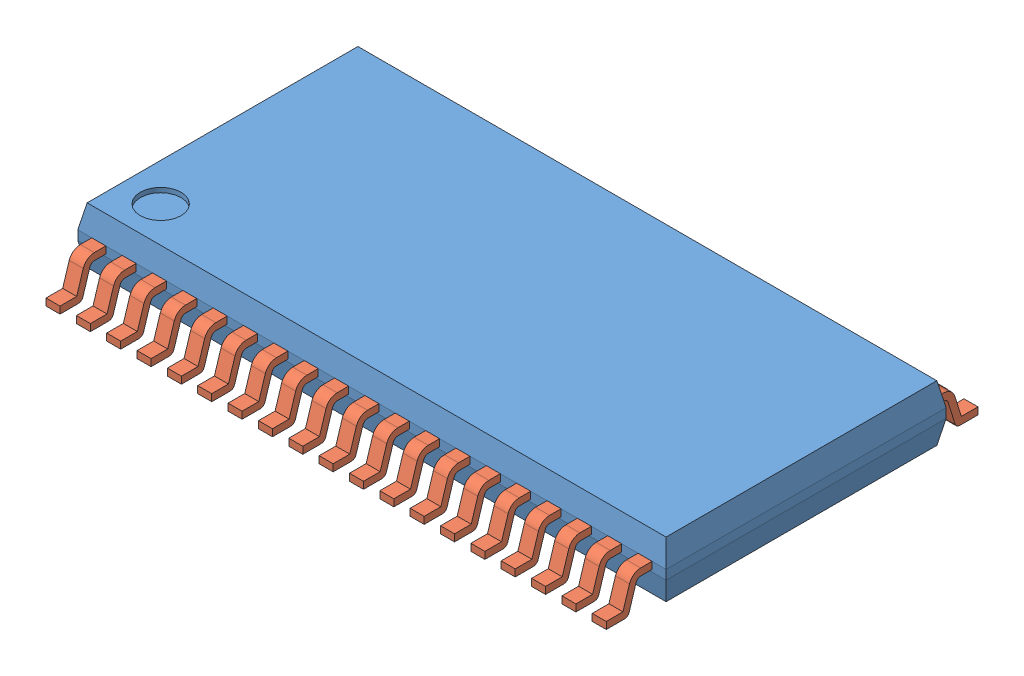
SolidWorks assembly U2, configuration Défaut. Lengths in mm.
Overall size (12.6 1.27 7.96).
39 component instances, 2 part files, 114 mates.
Components (placement in the parent):
- U2_Boitier-1: U2_Boitier [Défaut] at (4.9869 3.6612 3) size (12.6 1.2 6)
- U2_Pin-1: U2_Pin [Défaut] at (11.1369 3.5862 3.9812) x (0 0 -1) z (1 0 0) size (0.98 0.78 0.3)
- U2_Pin-2: U2_Pin [Défaut] at (10.4869 3.5862 3.9812) x (0 0 -1) z (1 0 0) size (0.98 0.78 0.3)
- U2_Pin-3: U2_Pin [Défaut] at (9.8369 3.5862 3.9812) x (0 0 -1) z (1 0 0) size (0.98 0.78 0.3)
- U2_Pin-4: U2_Pin [Défaut] at (9.1869 3.5862 3.9812) x (0 0 -1) z (1 0 0) size (0.98 0.78 0.3)
- U2_Pin-5: U2_Pin [Défaut] at (8.5369 3.5862 3.9812) x (0 0 -1) z (1 0 0) size (0.98 0.78 0.3)
- U2_Pin-6: U2_Pin [Défaut] at (7.8869 3.5862 3.9812) x (0 0 -1) z (1 0 0) size (0.98 0.78 0.3)
- U2_Pin-7: U2_Pin [Défaut] at (7.2369 3.5862 3.9812) x (0 0 -1) z (1 0 0) size (0.98 0.78 0.3)
- U2_Pin-8: U2_Pin [Défaut] at (6.5869 3.5862 3.9812) x (0 0 -1) z (1 0 0) size (0.98 0.78 0.3)
- U2_Pin-9: U2_Pin [Défaut] at (5.9369 3.5862 3.9812) x (0 0 -1) z (1 0 0) size (0.98 0.78 0.3)
- U2_Pin-12: U2_Pin [Défaut] at (11.7869 3.5862 3.9812) x (0 0 -1) z (1 0 0) size (0.98 0.78 0.3)
- U2_Pin-13: U2_Pin [Défaut] at (12.4369 3.5862 3.9812) x (0 0 -1) z (1 0 0) size (0.98 0.78 0.3)
- U2_Pin-14: U2_Pin [Défaut] at (13.0869 3.5862 3.9812) x (0 0 -1) z (1 0 0) size (0.98 0.78 0.3)
- U2_Pin-15: U2_Pin [Défaut] at (13.7369 3.5862 3.9812) x (0 0 -1) z (1 0 0) size (0.98 0.78 0.3)
- U2_Pin-16: U2_Pin [Défaut] at (14.3869 3.5862 3.9812) x (0 0 -1) z (1 0 0) size (0.98 0.78 0.3)
- U2_Pin-17: U2_Pin [Défaut] at (15.0369 3.5862 3.9812) x (0 0 -1) z (1 0 0) size (0.98 0.78 0.3)
- U2_Pin-18: U2_Pin [Défaut] at (15.6869 3.5862 3.9812) x (0 0 -1) z (1 0 0) size (0.98 0.78 0.3)
- U2_Pin-19: U2_Pin [Défaut] at (16.3369 3.5862 3.9812) x (0 0 -1) z (1 0 0) size (0.98 0.78 0.3)
- U2_Pin-21: U2_Pin [Défaut] at (5.2869 3.5862 3.9812) x (0 0 -1) z (1 0 0) size (0.98 0.78 0.3)
- U2_Pin-22: U2_Pin [Défaut] at (16.9869 3.5862 3.9812) x (0 0 -1) z (1 0 0) size (0.98 0.78 0.3)
- U2_Pin-23: U2_Pin [Défaut] at (11.4369 3.5862 -3.9812) x (0 0 1) z (-1 0 0) size (0.98 0.78 0.3)
- U2_Pin-24: U2_Pin [Défaut] at (12.0869 3.5862 -3.9812) x (0 0 1) z (-1 0 0) size (0.98 0.78 0.3)
- U2_Pin-26: U2_Pin [Défaut] at (12.7369 3.5862 -3.9812) x (0 0 1) z (-1 0 0) size (0.98 0.78 0.3)
- U2_Pin-27: U2_Pin [Défaut] at (13.3869 3.5862 -3.9812) x (0 0 1) z (-1 0 0) size (0.98 0.78 0.3)
- U2_Pin-28: U2_Pin [Défaut] at (14.0369 3.5862 -3.9812) x (0 0 1) z (-1 0 0) size (0.98 0.78 0.3)
- U2_Pin-29: U2_Pin [Défaut] at (14.6869 3.5862 -3.9812) x (0 0 1) z (-1 0 0) size (0.98 0.78 0.3)
- U2_Pin-30: U2_Pin [Défaut] at (15.3369 3.5862 -3.9812) x (0 0 1) z (-1 0 0) size (0.98 0.78 0.3)
- U2_Pin-31: U2_Pin [Défaut] at (15.9869 3.5862 -3.9812) x (0 0 1) z (-1 0 0) size (0.98 0.78 0.3)
- U2_Pin-32: U2_Pin [Défaut] at (16.6369 3.5862 -3.9812) x (0 0 1) z (-1 0 0) size (0.98 0.78 0.3)
- U2_Pin-33: U2_Pin [Défaut] at (17.2869 3.5862 -3.9812) x (0 0 1) z (-1 0 0) size (0.98 0.78 0.3)
- U2_Pin-34: U2_Pin [Défaut] at (10.7869 3.5862 -3.9812) x (0 0 1) z (-1 0 0) size (0.98 0.78 0.3)
- U2_Pin-35: U2_Pin [Défaut] at (10.1369 3.5862 -3.9812) x (0 0 1) z (-1 0 0) size (0.98 0.78 0.3)
- U2_Pin-36: U2_Pin [Défaut] at (9.4869 3.5862 -3.9812) x (0 0 1) z (-1 0 0) size (0.98 0.78 0.3)
- U2_Pin-37: U2_Pin [Défaut] at (8.8369 3.5862 -3.9812) x (0 0 1) z (-1 0 0) size (0.98 0.78 0.3)
- U2_Pin-38: U2_Pin [Défaut] at (8.1869 3.5862 -3.9812) x (0 0 1) z (-1 0 0) size (0.98 0.78 0.3)
- U2_Pin-39: U2_Pin [Défaut] at (7.5369 3.5862 -3.9812) x (0 0 1) z (-1 0 0) size (0.98 0.78 0.3)
- U2_Pin-40: U2_Pin [Défaut] at (6.8869 3.5862 -3.9812) x (0 0 1) z (-1 0 0) size (0.98 0.78 0.3)
- U2_Pin-41: U2_Pin [Défaut] at (6.2369 3.5862 -3.9812) x (0 0 1) z (-1 0 0) size (0.98 0.78 0.3)
- U2_Pin-42: U2_Pin [Défaut] at (5.5869 3.5862 -3.9812) x (0 0 1) z (-1 0 0) size (0.98 0.78 0.3)
Mates (geometry in assembly coordinates):
- Coïncidente1: coincident anti-aligned: plane of U2_Boitier-1 through (4.9869 4.8612 3) normal (0 0 1); plane of U2_Pin-1 through (11.4369 4.3612 3) normal (0 0 -1)
- Coïncidente2: coincident aligned: line of U2_Boitier-1 through (17.5869 4.3612 3) axis (-1 0 0); line of U2_Pin-1 through (11.4369 4.3612 3) axis (-1 0 0)
- Distance1: distance = 6.15 mm aligned: plane of U2_Pin-1 through (11.1369 3.6862 3.5874) normal (-1 0 0); plane of U2_Boitier-1 through (4.9869 4.8612 3) normal (-1 0 0)
- Coïncidente4: coincident anti-aligned: plane of U2_Boitier-1 through (4.9869 4.8612 3) normal (0 0 1); plane of U2_Pin-2 through (10.7869 4.3612 3) normal (0 0 -1)
- Coïncidente5: coincident aligned: line of U2_Boitier-1 through (17.5869 4.3612 3) axis (-1 0 0); line of U2_Pin-2 through (10.7869 4.3612 3) axis (-1 0 0)
- Distance2: distance = 0.35 mm anti-aligned: plane of U2_Pin-2 through (10.7869 3.6862 3.5874) normal (1 0 0); plane of U2_Pin-1 through (11.1369 3.6862 3.5874) normal (-1 0 0)
- Coïncidente7: coincident anti-aligned: plane of U2_Boitier-1 through (4.9869 4.8612 3) normal (0 0 1); plane of U2_Pin-3 through (10.1369 4.3612 3) normal (0 0 -1)
- Coïncidente8: coincident aligned: line of U2_Boitier-1 through (17.5869 4.3612 3) axis (-1 0 0); line of U2_Pin-3 through (10.1369 4.3612 3) axis (-1 0 0)
- Distance3: distance = 0.35 mm anti-aligned: plane of U2_Pin-3 through (10.1369 3.6862 3.5874) normal (1 0 0); plane of U2_Pin-2 through (10.4869 3.6862 3.5874) normal (-1 0 0)
- Coïncidente9: coincident anti-aligned: plane of U2_Boitier-1 through (4.9869 4.8612 3) normal (0 0 1); plane of U2_Pin-4 through (9.4869 4.3612 3) normal (0 0 -1)
- Coïncidente10: coincident aligned: line of U2_Boitier-1 through (17.5869 4.3612 3) axis (-1 0 0); line of U2_Pin-4 through (9.4869 4.3612 3) axis (-1 0 0)
- Distance4: distance = 0.35 mm anti-aligned: plane of U2_Pin-4 through (9.4869 3.6862 3.5874) normal (1 0 0); plane of U2_Pin-3 through (9.8369 3.6862 3.5874) normal (-1 0 0)
- Coïncidente11: coincident anti-aligned: plane of U2_Boitier-1 through (4.9869 4.8612 3) normal (0 0 1); plane of U2_Pin-5 through (8.8369 4.3612 3) normal (0 0 -1)
- Coïncidente12: coincident aligned: line of U2_Boitier-1 through (17.5869 4.3612 3) axis (-1 0 0); line of U2_Pin-5 through (8.8369 4.3612 3) axis (-1 0 0)
- Distance5: distance = 0.35 mm anti-aligned: plane of U2_Pin-5 through (8.8369 3.6862 3.5874) normal (1 0 0); plane of U2_Pin-4 through (9.1869 3.6862 3.5874) normal (-1 0 0)
- Coïncidente13: coincident anti-aligned: plane of U2_Boitier-1 through (4.9869 4.8612 3) normal (0 0 1); plane of U2_Pin-6 through (8.1869 4.3612 3) normal (0 0 -1)
- Coïncidente14: coincident aligned: line of U2_Boitier-1 through (17.5869 4.3612 3) axis (-1 0 0); line of U2_Pin-6 through (8.1869 4.3612 3) axis (-1 0 0)
- Distance6: distance = 0.35 mm anti-aligned: plane of U2_Pin-6 through (8.1869 3.6862 3.5874) normal (1 0 0); plane of U2_Pin-5 through (8.5369 3.6862 3.5874) normal (-1 0 0)
- Coïncidente15: coincident anti-aligned: plane of U2_Boitier-1 through (4.9869 4.8612 3) normal (0 0 1); plane of U2_Pin-7 through (7.5369 4.3612 3) normal (0 0 -1)
- Coïncidente16: coincident aligned: line of U2_Boitier-1 through (17.5869 4.3612 3) axis (-1 0 0); line of U2_Pin-7 through (7.5369 4.3612 3) axis (-1 0 0)
- Distance7: distance = 0.35 mm anti-aligned: plane of U2_Pin-7 through (7.5369 3.6862 3.5874) normal (1 0 0); plane of U2_Pin-6 through (7.8869 3.6862 3.5874) normal (-1 0 0)
- Coïncidente17: coincident anti-aligned: plane of U2_Boitier-1 through (4.9869 4.8612 3) normal (0 0 1); plane of U2_Pin-8 through (6.8869 4.3612 3) normal (0 0 -1)
- Coïncidente18: coincident aligned: line of U2_Boitier-1 through (17.5869 4.3612 3) axis (-1 0 0); line of U2_Pin-8 through (6.8869 4.3612 3) axis (-1 0 0)
- Distance8: distance = 0.35 mm anti-aligned: plane of U2_Pin-8 through (6.8869 3.6862 3.5874) normal (1 0 0); plane of U2_Pin-7 through (7.2369 3.6862 3.5874) normal (-1 0 0)
- Coïncidente19: coincident anti-aligned: plane of U2_Boitier-1 through (4.9869 4.8612 3) normal (0 0 1); plane of U2_Pin-9 through (6.2369 4.3612 3) normal (0 0 -1)
- Coïncidente20: coincident aligned: line of U2_Boitier-1 through (17.5869 4.3612 3) axis (-1 0 0); line of U2_Pin-9 through (6.2369 4.3612 3) axis (-1 0 0)
- Distance9: distance = 0.35 mm anti-aligned: plane of U2_Pin-9 through (6.2369 3.6862 3.5874) normal (1 0 0); plane of U2_Pin-8 through (6.5869 3.6862 3.5874) normal (-1 0 0)
- Coïncidente28: coincident anti-aligned: plane of U2_Boitier-1 through (4.9869 4.8612 3) normal (0 0 1); plane of U2_Pin-12 through (12.0869 4.3612 3) normal (0 0 -1)
- Coïncidente29: coincident aligned: line of U2_Boitier-1 through (17.5869 4.3612 3) axis (-1 0 0); line of U2_Pin-12 through (12.0869 4.3612 3) axis (-1 0 0)
- Distance11: distance = 0.35 mm anti-aligned: plane of U2_Pin-12 through (11.7869 3.6862 3.5874) normal (-1 0 0); plane of U2_Pin-1 through (11.4369 3.6862 3.5874) normal (1 0 0)
- Coïncidente31: coincident anti-aligned: plane of U2_Boitier-1 through (4.9869 4.8612 3) normal (0 0 1); plane of U2_Pin-13 through (12.7369 4.3612 3) normal (0 0 -1)
- Coïncidente32: coincident aligned: line of U2_Boitier-1 through (17.5869 4.3612 3) axis (-1 0 0); line of U2_Pin-13 through (12.7369 4.3612 3) axis (-1 0 0)
- Distance12: distance = 0.35 mm anti-aligned: plane of U2_Pin-13 through (12.4369 3.6862 3.5874) normal (-1 0 0); plane of U2_Pin-12 through (12.0869 3.6862 3.5874) normal (1 0 0)
- Coïncidente33: coincident anti-aligned: plane of U2_Boitier-1 through (4.9869 4.8612 3) normal (0 0 1); plane of U2_Pin-14 through (13.3869 4.3612 3) normal (0 0 -1)
- Coïncidente34: coincident aligned: line of U2_Boitier-1 through (17.5869 4.3612 3) axis (-1 0 0); line of U2_Pin-14 through (13.3869 4.3612 3) axis (-1 0 0)
- Distance13: distance = 0.35 mm anti-aligned: plane of U2_Pin-14 through (13.0869 3.6862 3.5874) normal (-1 0 0); plane of U2_Pin-13 through (12.7369 3.6862 3.5874) normal (1 0 0)
- Coïncidente35: coincident anti-aligned: plane of U2_Boitier-1 through (4.9869 4.8612 3) normal (0 0 1); plane of U2_Pin-15 through (14.0369 4.3612 3) normal (0 0 -1)
- Coïncidente36: coincident aligned: line of U2_Boitier-1 through (17.5869 4.3612 3) axis (-1 0 0); line of U2_Pin-15 through (14.0369 4.3612 3) axis (-1 0 0)
- Distance14: distance = 0.35 mm anti-aligned: plane of U2_Pin-15 through (13.7369 3.6862 3.5874) normal (-1 0 0); plane of U2_Pin-14 through (13.3869 3.6862 3.5874) normal (1 0 0)
- Coïncidente37: coincident anti-aligned: plane of U2_Boitier-1 through (4.9869 4.8612 3) normal (0 0 1); plane of U2_Pin-16 through (14.6869 4.3612 3) normal (0 0 -1)
- Coïncidente38: coincident aligned: line of U2_Boitier-1 through (17.5869 4.3612 3) axis (-1 0 0); line of U2_Pin-16 through (14.6869 4.3612 3) axis (-1 0 0)
- Distance15: distance = 0.35 mm anti-aligned: plane of U2_Pin-16 through (14.3869 3.6862 3.5874) normal (-1 0 0); plane of U2_Pin-15 through (14.0369 3.6862 3.5874) normal (1 0 0)
- Coïncidente39: coincident anti-aligned: plane of U2_Boitier-1 through (4.9869 4.8612 3) normal (0 0 1); plane of U2_Pin-17 through (15.3369 4.3612 3) normal (0 0 -1)
- Coïncidente40: coincident aligned: line of U2_Boitier-1 through (17.5869 4.3612 3) axis (-1 0 0); line of U2_Pin-17 through (15.3369 4.3612 3) axis (-1 0 0)
- Distance16: distance = 0.35 mm anti-aligned: plane of U2_Pin-17 through (15.0369 3.6862 3.5874) normal (-1 0 0); plane of U2_Pin-16 through (14.6869 3.6862 3.5874) normal (1 0 0)
- Coïncidente41: coincident anti-aligned: plane of U2_Boitier-1 through (4.9869 4.8612 3) normal (0 0 1); plane of U2_Pin-18 through (15.9869 4.3612 3) normal (0 0 -1)
- Coïncidente42: coincident aligned: line of U2_Boitier-1 through (17.5869 4.3612 3) axis (-1 0 0); line of U2_Pin-18 through (15.9869 4.3612 3) axis (-1 0 0)
- Distance17: distance = 0.35 mm anti-aligned: plane of U2_Pin-18 through (15.6869 3.6862 3.5874) normal (-1 0 0); line of U2_Pin-17 through (15.3369 3.6564 3.4919) axis (0 0.954693 -0.297593)
- Coïncidente43: coincident anti-aligned: plane of U2_Boitier-1 through (4.9869 4.8612 3) normal (0 0 1); plane of U2_Pin-19 through (16.6369 4.3612 3) normal (0 0 -1)
- Coïncidente44: coincident aligned: line of U2_Boitier-1 through (17.5869 4.3612 3) axis (-1 0 0); line of U2_Pin-19 through (16.6369 4.3612 3) axis (-1 0 0)
- Distance18: distance = 0.35 mm anti-aligned: plane of U2_Pin-19 through (16.3369 3.6862 3.5874) normal (-1 0 0); plane of U2_Pin-18 through (15.9869 3.6862 3.5874) normal (1 0 0)
- Coïncidente47: coincident anti-aligned: plane of U2_Boitier-1 through (4.9869 4.8612 3) normal (0 0 1); plane of U2_Pin-21 through (5.5869 4.3612 3) normal (0 0 -1)
- Coïncidente48: coincident aligned: line of U2_Boitier-1 through (17.5869 4.3612 3) axis (-1 0 0); line of U2_Pin-21 through (5.5869 4.3612 3) axis (-1 0 0)
- Distance20: distance = 0.35 mm anti-aligned: plane of U2_Pin-21 through (5.5869 3.6862 3.5874) normal (1 0 0); plane of U2_Pin-9 through (5.9369 3.6862 3.5874) normal (-1 0 0)
- Coïncidente49: coincident anti-aligned: plane of U2_Boitier-1 through (4.9869 4.8612 3) normal (0 0 1); plane of U2_Pin-22 through (17.2869 4.3612 3) normal (0 0 -1)
- Coïncidente50: coincident aligned: line of U2_Boitier-1 through (17.5869 4.3612 3) axis (-1 0 0); line of U2_Pin-22 through (17.2869 4.3612 3) axis (-1 0 0)
- Distance21: distance = 0.35 mm anti-aligned: plane of U2_Pin-22 through (16.9869 3.6862 3.5874) normal (-1 0 0); plane of U2_Pin-19 through (16.6369 3.6862 3.5874) normal (1 0 0)
- Coïncidente51: coincident anti-aligned: plane of U2_Boitier-1 through (4.9869 4.8612 -3) normal (0 0 -1); plane of U2_Pin-23 through (11.1369 4.3612 -3) normal (0 0 1)
- Coïncidente52: coincident aligned: line of U2_Boitier-1 through (4.9869 4.3612 -3) axis (1 0 0); line of U2_Pin-23 through (11.1369 4.3612 -3) axis (1 0 0)
- Distance22: distance = 6.15 mm aligned: plane of U2_Pin-23 through (11.4369 3.6862 -3.5874) normal (1 0 0); plane of U2_Boitier-1 through (17.5869 4.8612 3) normal (1 0 0)
- Coïncidente54: coincident anti-aligned: plane of U2_Boitier-1 through (4.9869 4.8612 -3) normal (0 0 -1); plane of U2_Pin-24 through (11.7869 4.3612 -3) normal (0 0 1)
- Coïncidente55: coincident aligned: line of U2_Boitier-1 through (4.9869 4.3612 -3) axis (1 0 0); line of U2_Pin-24 through (11.7869 4.3612 -3) axis (1 0 0)
- Distance25: distance = 0.35 mm anti-aligned: plane of U2_Pin-23 through (11.4369 3.6862 -3.5874) normal (1 0 0); plane of U2_Pin-24 through (11.7869 3.6862 -3.5874) normal (-1 0 0)
- Coïncidente60: coincident anti-aligned: plane of U2_Boitier-1 through (4.9869 4.8612 -3) normal (0 0 -1); plane of U2_Pin-26 through (12.4369 4.3612 -3) normal (0 0 1)
- Coïncidente61: coincident aligned: line of U2_Boitier-1 through (4.9869 4.3612 -3) axis (1 0 0); line of U2_Pin-26 through (12.4369 4.3612 -3) axis (1 0 0)
- Distance26: distance = 0.35 mm anti-aligned: plane of U2_Pin-24 through (12.0869 3.6862 -3.5874) normal (1 0 0); plane of U2_Pin-26 through (12.4369 3.6862 -3.5874) normal (-1 0 0)
- Coïncidente62: coincident anti-aligned: plane of U2_Boitier-1 through (4.9869 4.8612 -3) normal (0 0 -1); plane of U2_Pin-27 through (13.0869 4.3612 -3) normal (0 0 1)
- Coïncidente63: coincident aligned: line of U2_Boitier-1 through (4.9869 4.3612 -3) axis (1 0 0); line of U2_Pin-27 through (13.0869 4.3612 -3) axis (1 0 0)
- Distance27: distance = 0.35 mm anti-aligned: plane of U2_Pin-26 through (12.7369 3.6862 -3.5874) normal (1 0 0); plane of U2_Pin-27 through (13.0869 3.6862 -3.5874) normal (-1 0 0)
- Coïncidente64: coincident anti-aligned: plane of U2_Boitier-1 through (4.9869 4.8612 -3) normal (0 0 -1); plane of U2_Pin-28 through (13.7369 4.3612 -3) normal (0 0 1)
- Coïncidente65: coincident aligned: line of U2_Boitier-1 through (4.9869 4.3612 -3) axis (1 0 0); line of U2_Pin-28 through (13.7369 4.3612 -3) axis (1 0 0)
- Distance28: distance = 0.35 mm anti-aligned: plane of U2_Pin-27 through (13.3869 3.6862 -3.5874) normal (1 0 0); plane of U2_Pin-28 through (13.7369 3.6862 -3.5874) normal (-1 0 0)
- Coïncidente66: coincident anti-aligned: plane of U2_Boitier-1 through (4.9869 4.8612 -3) normal (0 0 -1); plane of U2_Pin-29 through (14.3869 4.3612 -3) normal (0 0 1)
- Coïncidente67: coincident aligned: line of U2_Boitier-1 through (4.9869 4.3612 -3) axis (1 0 0); line of U2_Pin-29 through (14.3869 4.3612 -3) axis (1 0 0)
- Distance29: distance = 0.35 mm anti-aligned: plane of U2_Pin-28 through (14.0369 3.6862 -3.5874) normal (1 0 0); plane of U2_Pin-29 through (14.3869 3.6862 -3.5874) normal (-1 0 0)
- Coïncidente68: coincident anti-aligned: plane of U2_Boitier-1 through (4.9869 4.8612 -3) normal (0 0 -1); plane of U2_Pin-30 through (15.0369 4.3612 -3) normal (0 0 1)
- Coïncidente69: coincident aligned: line of U2_Boitier-1 through (4.9869 4.3612 -3) axis (1 0 0); line of U2_Pin-30 through (15.0369 4.3612 -3) axis (1 0 0)
- Distance30: distance = 0.35 mm anti-aligned: plane of U2_Pin-29 through (14.6869 3.6862 -3.5874) normal (1 0 0); plane of U2_Pin-30 through (15.0369 3.6862 -3.5874) normal (-1 0 0)
- Coïncidente70: coincident anti-aligned: plane of U2_Boitier-1 through (4.9869 4.8612 -3) normal (0 0 -1); plane of U2_Pin-31 through (15.6869 4.3612 -3) normal (0 0 1)
- Coïncidente71: coincident aligned: line of U2_Boitier-1 through (4.9869 4.3612 -3) axis (1 0 0); line of U2_Pin-31 through (15.6869 4.3612 -3) axis (1 0 0)
- Distance31: distance = 0.35 mm anti-aligned: plane of U2_Pin-30 through (15.3369 3.6862 -3.5874) normal (1 0 0); plane of U2_Pin-31 through (15.6869 3.6862 -3.5874) normal (-1 0 0)
- Coïncidente72: coincident anti-aligned: plane of U2_Boitier-1 through (4.9869 4.8612 -3) normal (0 0 -1); plane of U2_Pin-32 through (16.3369 4.3612 -3) normal (0 0 1)
- Coïncidente73: coincident aligned: line of U2_Boitier-1 through (4.9869 4.3612 -3) axis (1 0 0); line of U2_Pin-32 through (16.3369 4.3612 -3) axis (1 0 0)
- Distance32: distance = 0.35 mm anti-aligned: plane of U2_Pin-31 through (15.9869 3.6862 -3.5874) normal (1 0 0); plane of U2_Pin-32 through (16.3369 3.6862 -3.5874) normal (-1 0 0)
- Coïncidente74: coincident anti-aligned: plane of U2_Boitier-1 through (4.9869 4.8612 -3) normal (0 0 -1); plane of U2_Pin-33 through (16.9869 4.3612 -3) normal (0 0 1)
- Coïncidente75: coincident aligned: line of U2_Boitier-1 through (4.9869 4.3612 -3) axis (1 0 0); line of U2_Pin-33 through (16.9869 4.3612 -3) axis (1 0 0)
- Distance33: distance = 0.35 mm anti-aligned: plane of U2_Pin-32 through (16.6369 3.6862 -3.5874) normal (1 0 0); plane of U2_Pin-33 through (16.9869 3.6862 -3.5874) normal (-1 0 0)
- Coïncidente76: coincident anti-aligned: plane of U2_Boitier-1 through (4.9869 4.8612 -3) normal (0 0 -1); plane of U2_Pin-34 through (10.4869 4.3612 -3) normal (0 0 1)
- Coïncidente78: coincident aligned: line of U2_Boitier-1 through (4.9869 4.3612 -3) axis (1 0 0); line of U2_Pin-34 through (10.4869 4.3612 -3) axis (1 0 0)
- Distance34: distance = 0.35 mm anti-aligned: plane of U2_Pin-23 through (11.1369 3.6862 -3.5874) normal (-1 0 0); plane of U2_Pin-34 through (10.7869 3.6862 -3.5874) normal (1 0 0)
- Coïncidente80: coincident anti-aligned: plane of U2_Boitier-1 through (4.9869 4.8612 -3) normal (0 0 -1); plane of U2_Pin-35 through (9.8369 4.3612 -3) normal (0 0 1)
- Coïncidente81: coincident aligned: line of U2_Boitier-1 through (4.9869 4.3612 -3) axis (1 0 0); line of U2_Pin-35 through (9.8369 4.3612 -3) axis (1 0 0)
- Distance35: distance = 0.35 mm anti-aligned: plane of U2_Pin-34 through (10.4869 3.6862 -3.5874) normal (-1 0 0); plane of U2_Pin-35 through (10.1369 3.6862 -3.5874) normal (1 0 0)
- Coïncidente82: coincident anti-aligned: plane of U2_Boitier-1 through (4.9869 4.8612 -3) normal (0 0 -1); plane of U2_Pin-36 through (9.1869 4.3612 -3) normal (0 0 1)
- Coïncidente83: coincident aligned: line of U2_Boitier-1 through (4.9869 4.3612 -3) axis (1 0 0); line of U2_Pin-36 through (9.1869 4.3612 -3) axis (1 0 0)
- Distance36: distance = 0.35 mm anti-aligned: plane of U2_Pin-35 through (9.8369 3.6862 -3.5874) normal (-1 0 0); plane of U2_Pin-36 through (9.4869 3.6862 -3.5874) normal (1 0 0)
- Coïncidente84: coincident anti-aligned: plane of U2_Boitier-1 through (4.9869 4.8612 -3) normal (0 0 -1); plane of U2_Pin-37 through (8.5369 4.3612 -3) normal (0 0 1)
- Coïncidente85: coincident aligned: line of U2_Boitier-1 through (4.9869 4.3612 -3) axis (1 0 0); line of U2_Pin-37 through (8.5369 4.3612 -3) axis (1 0 0)
- Distance37: distance = 0.35 mm anti-aligned: plane of U2_Pin-36 through (9.1869 3.6862 -3.5874) normal (-1 0 0); plane of U2_Pin-37 through (8.8369 3.6862 -3.5874) normal (1 0 0)
- Coïncidente86: coincident anti-aligned: plane of U2_Boitier-1 through (4.9869 4.8612 -3) normal (0 0 -1); plane of U2_Pin-38 through (7.8869 4.3612 -3) normal (0 0 1)
- Coïncidente87: coincident aligned: line of U2_Boitier-1 through (4.9869 4.3612 -3) axis (1 0 0); line of U2_Pin-38 through (7.8869 4.3612 -3) axis (1 0 0)
- Distance38: distance = 0.35 mm anti-aligned: plane of U2_Pin-37 through (8.5369 3.6862 -3.5874) normal (-1 0 0); plane of U2_Pin-38 through (8.1869 3.6862 -3.5874) normal (1 0 0)
- Coïncidente88: coincident anti-aligned: plane of U2_Boitier-1 through (4.9869 4.8612 -3) normal (0 0 -1); plane of U2_Pin-39 through (7.2369 4.3612 -3) normal (0 0 1)
- Coïncidente89: coincident aligned: line of U2_Boitier-1 through (4.9869 4.3612 -3) axis (1 0 0); line of U2_Pin-39 through (7.2369 4.3612 -3) axis (1 0 0)
- Distance39: distance = 0.35 mm anti-aligned: plane of U2_Pin-38 through (7.8869 3.6862 -3.5874) normal (-1 0 0); plane of U2_Pin-39 through (7.5369 3.6862 -3.5874) normal (1 0 0)
- Coïncidente90: coincident anti-aligned: plane of U2_Boitier-1 through (4.9869 4.8612 -3) normal (0 0 -1); plane of U2_Pin-40 through (6.5869 4.3612 -3) normal (0 0 1)
- Coïncidente91: coincident aligned: line of U2_Boitier-1 through (4.9869 4.3612 -3) axis (1 0 0); line of U2_Pin-40 through (6.5869 4.3612 -3) axis (1 0 0)
- Distance40: distance = 0.35 mm anti-aligned: line of U2_Pin-39 through (7.2369 4.2112 -3.2454) axis (0 0 1); plane of U2_Pin-40 through (6.8869 3.6862 -3.5874) normal (1 0 0)
- Coïncidente92: coincident anti-aligned: plane of U2_Boitier-1 through (4.9869 4.8612 -3) normal (0 0 -1); plane of U2_Pin-41 through (5.9369 4.3612 -3) normal (0 0 1)
- Coïncidente93: coincident aligned: line of U2_Boitier-1 through (4.9869 4.3612 -3) axis (1 0 0); line of U2_Pin-41 through (5.9369 4.3612 -3) axis (1 0 0)
- Distance41: distance = 0.35 mm anti-aligned: plane of U2_Pin-40 through (6.5869 3.6862 -3.5874) normal (-1 0 0); plane of U2_Pin-41 through (6.2369 3.6862 -3.5874) normal (1 0 0)
- Coïncidente94: coincident anti-aligned: plane of U2_Boitier-1 through (4.9869 4.8612 -3) normal (0 0 -1); plane of U2_Pin-42 through (5.2869 4.3612 -3) normal (0 0 1)
- Coïncidente95: coincident aligned: line of U2_Boitier-1 through (4.9869 4.3612 -3) axis (1 0 0); line of U2_Pin-42 through (5.2869 4.3612 -3) axis (1 0 0)
- Distance42: distance = 0.35 mm anti-aligned: plane of U2_Pin-41 through (5.9369 3.6862 -3.5874) normal (-1 0 0); plane of U2_Pin-42 through (5.5869 3.6862 -3.5874) normal (1 0 0)
